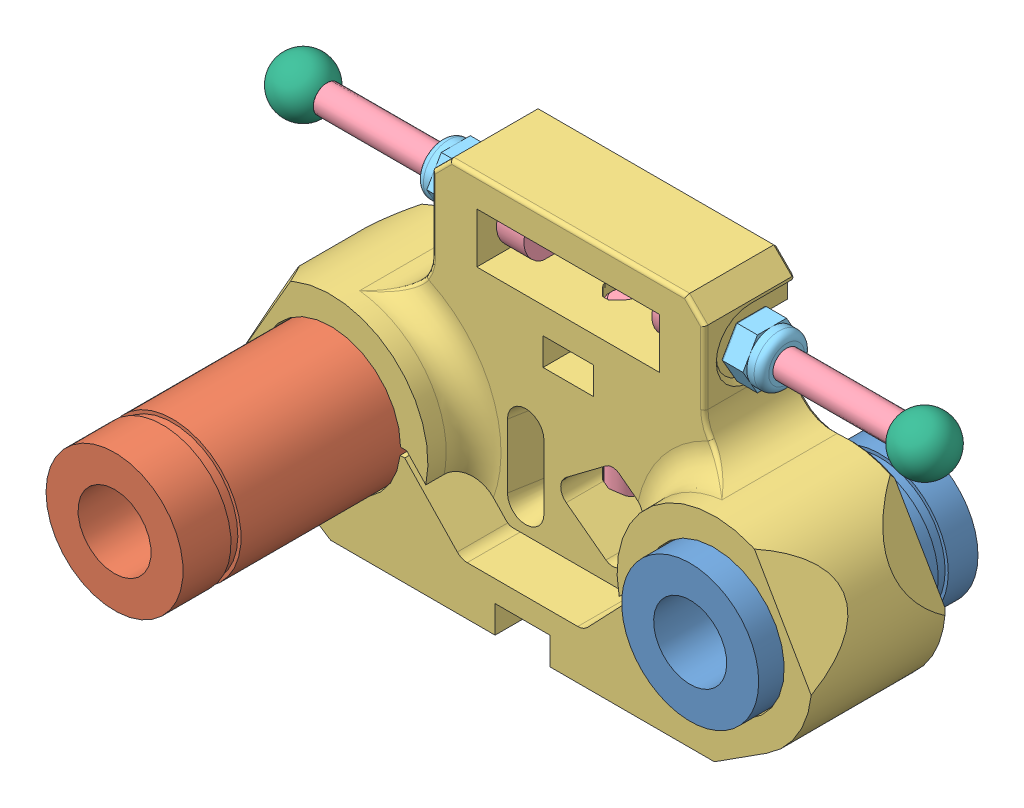
SolidWorks assembly carriage-assy, configuration Default. Lengths in mm.
Overall size (74 37.65 45).
11 component instances, 7 part files, 23 mates.
Components (placement in the parent):
- 287-1: 287 [Default] at (21.47 12.65 17.65) x (0.748446 0.663196 0) z (0 0 -1) size (15 15 24)
- 1182-2: 1182 [Default] at (-20.53 12.65 38.65) x (-0.937238 -0.348691 0) z (0 0 -1) size (15 15 45)
- 1304-1: 1304 [Default] at (0.47 12.65 0) size (63.3 37.65 15)
- 112-1: 112 [Default] at (-9.53 31.65 5) x (0 0.942277 -0.334835) z (1 0 0) size (5.7 5.7 28)
- 112-2: 112 [Default] at (10.47 31.65 5) x (0 -0.423071 0.906097) z (-1 0 0) size (5.7 5.7 28)
- 112-3: 112 [Default] at (0.47 3 4) x (-0.642262 0 -0.766485) z (0 -1 0) size (5.7 5.7 28)
- 204-4: 204 [Default] at (15.37 31.65 5) x (0 0 -1) z (1 0 0) size (6.35 5.5 4)
- 204-5: 204 [Default] at (-14.43 31.65 5) x (0 0.866025 0.5) z (-1 0 0) size (6.35 5.5 4)
- 1191-1: 1191 [Default] at (34.47 31.65 5) x (-1 0 0) z (0 0 1) size (5.6 6 6)
- 1191-2: 1191 [Default] at (-33.53 31.65 5) size (5.6 6 6)
- 258-1: 258 [Default] at (0.47 25.4 4) x (0 0 -1) z (0 -1 0) size (6.35 5.5 2.4)
Mates (geometry in assembly coordinates):
- Coincident11: coincident aligned: plane of 287-1 through (24.4638 15.3028 -6.35) normal (0 0 -1); plane of 1182-2 through (-24.2789 11.2552 -6.35) normal (0 0 -1)
- Concentric86: concentric aligned: cylinder of 287-1 through (21.47 12.65 17.65) axis (0 0 -1) radius 7.5; cylinder of 1304-1 through (21.47 12.65 15) axis (0 0 -1) radius 7.65
- Coincident10: coincident aligned: plane of 1182-2 through (-27.2312 10.1569 0) normal (0 0 -1); plane of 1304-1 through (-20.53 12.65 0) normal (0 0 -1)
- Concentric87: concentric aligned: cylinder of 1182-2 through (-20.53 12.65 38.65) axis (0 0 -1) radius 7.5; cylinder of 1304-1 through (-20.53 12.65 15) axis (0 0 -1) radius 7.65
- Concentric79: concentric anti-aligned: cylinder of 1304-1 through (32.12 31.65 5) axis (-1 0 0) radius 1.6; cylinder of 112-1 through (-34.53 31.65 5) axis (1 0 0) radius 1.5
- Coincident63: coincident anti-aligned: plane of 1304-1 through (-9.53 12.65 0) normal (1 0 0); plane of 112-1 through (-9.53 31.65 5) normal (-1 0 0)
- Coincident64: coincident anti-aligned: plane of 1304-1 through (10.47 12.65 0) normal (-1 0 0); plane of 112-2 through (10.47 31.65 5) normal (1 0 0)
- Concentric80: concentric aligned: cylinder of 1304-1 through (32.12 31.65 5) axis (-1 0 0) radius 1.6; cylinder of 112-2 through (35.47 31.65 5) axis (-1 0 0) radius 1.5
- Concentric232: concentric aligned: cylinder of 1304-1 through (0.47 30 4) axis (0 -1 0) radius 1.6; cylinder of 112-3 through (0.47 28 4) axis (0 -1 0) radius 1.5
- Coincident189: coincident anti-aligned: plane of 1304-1 through (0.47 3 4) normal (0 -1 0); plane of 112-3 through (0.47 3 4) normal (0 1 0)
- Concentric235: concentric aligned: cylinder of 112-2 through (35.47 31.65 5) axis (-1 0 0) radius 1.5; cylinder of 204-4 through (17.77 31.65 5) axis (-1 0 0) radius 1.25
- Concentric236: concentric aligned: cylinder of 112-1 through (-34.53 31.65 5) axis (1 0 0) radius 1.5; cylinder of 204-5 through (-16.83 31.65 5) axis (1 0 0) radius 1.25
- Coincident192: coincident anti-aligned: plane of 1304-1 through (-14.43 27.65 15) normal (-1 0 0); plane of 204-5 through (-14.43 31.65 5) normal (1 0 0)
- Coincident193: coincident anti-aligned: plane of 1304-1 through (15.37 27.65 15) normal (1 0 0); plane of 204-4 through (15.37 31.65 5) normal (-1 0 0)
- Concentric237: concentric aligned: cylinder of 112-2 through (35.47 31.65 5) axis (-1 0 0) radius 1.5; cylinder of 1191-1 through (31.47 31.65 5) axis (-1 0 0) radius 1.25
- Coincident194: coincident anti-aligned: plane of 112-2 through (35.47 31.65 5) normal (1 0 0); circle of 1191-1
- Concentric238: concentric aligned: cylinder of 112-1 through (-34.53 31.65 5) axis (1 0 0) radius 1.5; cylinder of 1191-2 through (-30.53 31.65 5) axis (1 0 0) radius 1.25
- Coincident195: coincident anti-aligned: plane of 112-1 through (-34.53 31.65 5) normal (-1 0 0); circle of 1191-2
- Coincident196: coincident anti-aligned: plane of 1304-1 through (-20.53 12.65 0) normal (0 0 -1); plane of assembly through (0 0 0) normal (0 0 1)
- Coincident197: coincident anti-aligned: plane of 1304-1 through (-20.53 0 15) normal (0 -1 0); plane of assembly through (0 0 0) normal (0 1 0)
- Concentric239: concentric anti-aligned: cylinder of 112-3 through (0.47 28 4) axis (0 -1 0) radius 1.5; cylinder of 258-1 through (0.47 23 4) axis (0 1 0) radius 1.25
- Coincident198: coincident anti-aligned: plane of 1304-1 through (0.47 23 0) normal (0 1 0); plane of 258-1 through (0.47 23 4) normal (0 -1 0)
- Parallel1: parallel anti-aligned: plane of 1304-1 through (3.22 26 2.1123) normal (-1 0 0); plane of 258-1 through (3.22 23 2.4123) normal (1 0 0)
